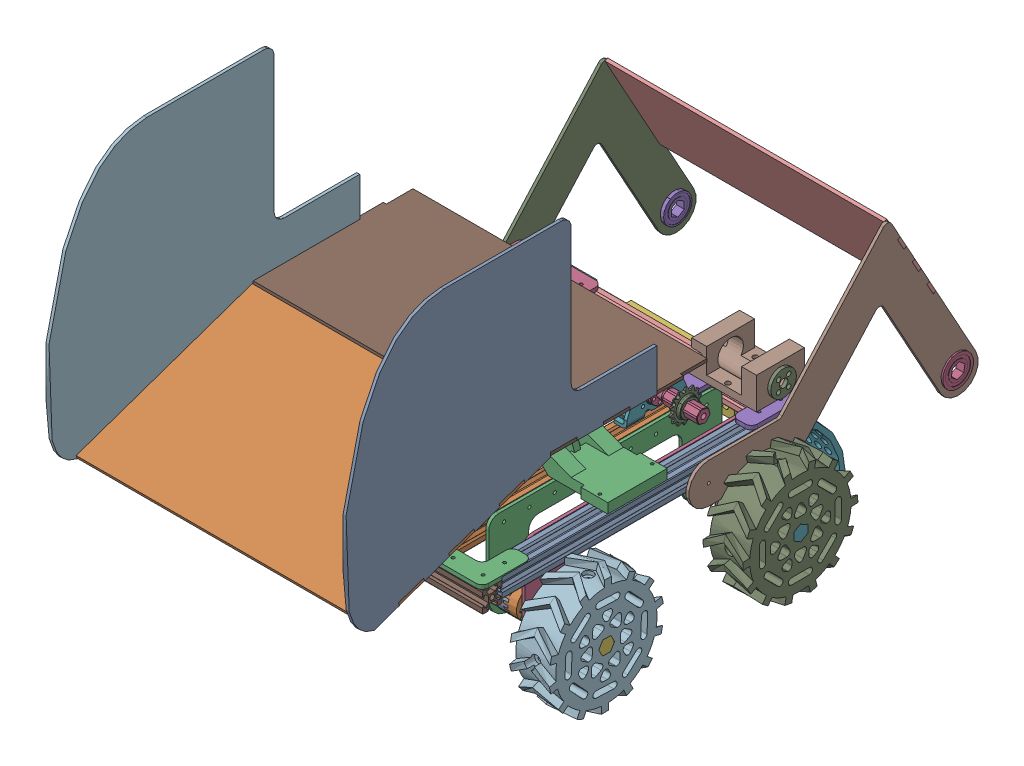
SolidWorks assembly Ensamblaje GOOOD BUENO V1, configuration Predeterminado. Lengths in mm.
Overall size (363.3 412.86 636.58).
70 component instances, 22 part files, 182 mates.
Components (placement in the parent):
- Perfil paredes-1: Perfil paredes [Predeterminado] at (-2.853 0.3396 -139.6276) size (20 20 280)
- Perfil paredes-3: Perfil paredes [Predeterminado] at (-62.853 -0.5145 -139.6276) size (20 20 280)
- PartCut-1: PartCut [Default] at (-49.853 -0.5145 -20.1572) x (0 0 1) z (0 -1 0) size (234 3 90)
- PartCut-2: PartCut [Default] at (-12.853 0.3396 -19.6675) x (0 0 1) z (0 -1 0) size (234 3 90)
- balero1-1: balero1 [Default] at (9.9745 -61.0728 77.1097) x (0 0.038595 0.999255) z (0 -0.999255 0.038595) size (30 21.24 30)
- eje hex_1-3: eje hex_1 [Default] at (-56.203 -60.313 75.8061) x (0 0.884678 0.466203) z (0 0.466203 -0.884678) size (16 105 13.86)
- eje hex_1-4: eje hex_1 [Default] at (-56.203 -61.5657 -116.9555) x (0 -0.5 -0.866025) z (0 -0.866025 0.5) size (16 105 13.86)
- balero1-2: balero1 [Default] at (-11.2655 -60.3108 -117.6536) x (0 -0.5 -0.866025) z (0 -0.866025 0.5) size (30 21.24 30)
- Llanta traccion-1: Llanta traccion [Default] at (28.797 -59.8526 -117.1472) x (0 0 -1) z (-1 0 0) size (115.27 115.22 40)
- sprocket-1: sprocket [Predeterminado] at (-23.9655 -60.2279 -117.7972) x (0 -0.994763 0.102207) z (-1 0 0) size (31.63 31.06 9.53)
- sprocket-2: sprocket [Predeterminado] at (-14.4405 -60.2279 -117.7972) x (0 -0.802979 0.596008) z (-1 0 0) size (31.63 31.06 9.53)
- Llanta traccion-2: Llanta traccion [Default] at (28.797 -60.479 77.5038) x (0 -0.999255 0.038595) z (-1 0 0) size (115.27 115.22 40)
- balero2-2: balero2 [Default] at (-48.2655 -61.1398 77.2368) x (0 -0.846083 0.533052) z (0 0.533052 0.846083) size (30 13 30)
- balero2-3: balero2 [Default] at (-39.7673 -61.1398 77.2368) x (0 -0.985001 0.172549) z (0 0.172549 0.985001) size (30 13 30)
- sprocket-3: sprocket [Predeterminado] at (-22.0048 -61.1398 77.2368) x (0 -0.703764 0.710434) z (-1 0 0) size (31.63 31.06 9.53)
- 1-2in Hex Adapter (REV-41-1620)-1: 1-2in Hex Adapter (REV-41-1620) [Default] at (-56.103 29.9855 -79.8) x (0 -0.955199 -0.295963) z (0 -0.295963 0.955199) size (22 46.85 22)
- 1-2in Hex Adapter (REV-41-1620)-2: 1-2in Hex Adapter (REV-41-1620) [Default] at (-206.603 30.8396 79.8) x (0 -0.552095 0.833781) z (0 -0.833781 -0.552095) size (22 46.85 22)
- UltraPlanetary Bent-1: UltraPlanetary Bent [Default] at (-204.853 30.8396 79.8) x (0 0 -1) z (1 0 0) size (60.41 41.01 15)
- UltraPlanetary Bent-2: UltraPlanetary Bent [Default] at (-60.853 29.9855 -79.8) x (0 0 1) z (-1 0 0) size (60.41 41.01 15)
- sprocket-21: sprocket [Predeterminado] at (-243.0667 30.8104 79.7982) x (0 0.061237 -0.998123) z (-1 0 0) size (31.63 31.06 9.53)
- sprocket-22: sprocket [Predeterminado] at (-29.5408 30.007 -79.8199) x (0 -0.679246 -0.733911) z (-1 0 0) size (31.63 31.06 9.53)
- Perfil paredes2-3: Perfil paredes2 [Predeterminado] at (-272.853 0.3396 -149.6276) x (0 0 -1) z (1 0 0) size (20 20 280)
- Perfil paredes2-4: Perfil paredes2 [Predeterminado] at (7.147 -3.1467 150.3724) x (0 0 1) z (-1 0 0) size (20 20 280)
- Perfil paredes-16: Perfil paredes [Predeterminado] at (-262.853 0.3396 -139.6276) size (20 20 280)
- Perfil paredes-17: Perfil paredes [Predeterminado] at (-202.853 0.3396 -139.6276) size (20 20 280)
- pieza soporte H-30: pieza soporte H [Predeterminado] at (-273.041 10.8533 133.768) x (1 0 0) z (0 -1 0) size (80 50 4)
- pieza soporte H-31: pieza soporte H [Predeterminado] at (-73.041 10.8533 133.768) x (1 0 0) z (0 -1 0) size (80 50 4)
- pieza soporte H-33: pieza soporte H [Predeterminado] at (-273.041 10.3396 -133.0232) x (1 0 0) z (0 1 0) size (80 50 4)
- pieza soporte H-34: pieza soporte H [Predeterminado] at (-73.041 10.3396 -133.0232) x (1 0 0) z (0 1 0) size (80 50 4)
- Motor REV-2: Motor REV [Predeterminado] at (-150.4708 15.4335 -105.4154) x (0 0.973917 -0.226904) z (0 0.226904 0.973917) size (39.5 129.75 43.54)
- Motor REV-3: Motor REV [Predeterminado] at (-112.2352 28.9925 50.3977) x (0 -0.939212 0.343339) z (0 0.343339 0.939212) size (39.5 129.75 43.54)
- Bumper (1)-3: Bumper (1) [Predeterminado] at (-167.853 -42.8554 -184.0714) size (70 88.26 45)
- Bumper (1)-4: Bumper (1) [Predeterminado] at (-272.853 -42.8554 -184.8214) size (70 88.26 45)
- IntakePropuesta-1: IntakePropuesta [Default] at (7.147 -21.3212 -199.703) x (0 0 -1) z (1 0 0) size (290.34 185.38 3)
- IntakePropuesta-2: IntakePropuesta [Default] at (-275.853 -21.3212 -199.703) x (0 0 -1) z (1 0 0) size (290.34 185.38 3)
- TapaRob-1: TapaRob [Default] at (-132.868 76.0202 -273.85) x (1 0 0) z (0 -0.48294 0.875654) size (286.03 114 3)
- FINAL-2: FINAL [Default] at (-137.1255 79.252 63.0539) x (0 0 1) z (-1 0 0) size (367.05 282.22 301.07)
  - placa-3: placa [Default] at (-104.5076 17.8118 2.7979) x (0 0 -1) z (0 -1 0) size (301.07 160.28 3)
  - LADOCAJA-16: LADOCAJA [Default] at (139.2351 16.3901 150.3351) x (0 0 1) z (-1 0 0) size (3 261.79 313.65)
  - LADOCAJA-17: LADOCAJA [Default] at (139.2351 16.3901 -147.7393) x (0 0 1) z (-1 0 0) size (3 261.79 313.65)
  - placanaja-1: placanaja [Predeterminado] at (153.6015 -28.7527 14.1489) x (0 0 -1) z (0.945056 -0.326908 0) size (301.07 3 186.9)
  - soporteizq-1: soporteizq [Predeterminado] at (-59.1696 -68.9123 -269.6703) x (0 0 -1) z (1 0 0) size (133.23 83.72 79.38)
- WCP-0783 (1)-29: WCP-0783 (1) [Default] at (3.797 -35.3661 -312.4416) x (0 -0.363378 0.931642) z (0 0.931642 0.363378) size (31.12 7.94 31.12)
- WCP-0783 (1)-30: WCP-0783 (1) [Default] at (-269.503 -35.3661 -312.4416) x (0 0.520565 -0.853822) z (0 0.853822 0.520565) size (31.12 7.94 31.12)
- WCP-0783 (1)-31: WCP-0783 (1) [Default] at (-46.503 -60.5145 -117.1572) x (0 -0.999907 0.013654) z (0 -0.013654 -0.999907) size (31.12 7.94 31.12)
- WCP-0783 (1)-32: WCP-0783 (1) [Default] at (-19.203 -59.6604 -116.6675) x (0 -0.480547 -0.876969) z (0 -0.876969 0.480547) size (31.12 7.94 31.12)
- WCP-0783 (1)-33: WCP-0783 (1) [Default] at (-246.503 -59.6604 -116.6675) x (0 -0.163854 -0.986485) z (0 0.986485 -0.163854) size (31.12 7.94 31.12)
- WCP-0783 (1)-34: WCP-0783 (1) [Default] at (-219.203 -60.5145 -117.1572) x (0 0.833867 0.551965) z (0 0.551965 -0.833867) size (31.12 7.94 31.12)
- WCP-0783 (1)-35: WCP-0783 (1) [Default] at (-219.203 -60.5145 76.8428) x (0 0.833867 0.551965) z (0 0.551965 -0.833867) size (31.12 7.94 31.12)
- WCP-0783 (1)-37: WCP-0783 (1) [Default] at (-246.503 -59.6604 77.3325) x (0 0.191015 -0.981587) z (0 0.981587 0.191015) size (31.12 7.94 31.12)
- WCP-0783 (1)-38: WCP-0783 (1) [Default] at (-19.203 -59.6604 77.3325) x (0 -0.3642 -0.931321) z (0 -0.931321 0.3642) size (31.12 7.94 31.12)
- WCP-0783 (1)-39: WCP-0783 (1) [Default] at (-46.503 -60.5145 76.8428) x (0 -0.463002 -0.886357) z (0 0.886357 -0.463002) size (31.12 7.94 31.12)
- balero2-24: balero2 [Default] at (-49.8156 -59.6604 -116.6675) x (0 -0.890112 -0.455741) z (0 -0.455741 0.890112) size (30 13 30)
- sprocket-26: sprocket [Predeterminado] at (-33.4905 -59.6604 -116.6675) x (0 -0.996368 0.085151) z (-1 0 0) size (31.63 31.06 9.53)
- balero2-26: balero2 [Default] at (-236.978 -59.6604 -116.6675) x (0 0.645951 -0.763379) z (0 -0.763379 -0.645951) size (30 13 30)
- balero2-29: balero2 [Default] at (-232.203 -60.5145 -117.1572) x (0 -0.573036 -0.819531) z (0 -0.819531 0.573036) size (30 13 30)
- sprocket-27: sprocket [Predeterminado] at (-234.1761 -59.6604 77.3325) x (0 -0.620534 0.78418) z (1 0 0) size (31.63 31.06 9.53)
- soportebump-3: soportebump [Default] at (-37.7876 -69.4237 -220.7073) x (1 0 0) z (0 0.006058 0.999982) size (73.25 131.02 90.26)
- soportder-1: soportder [Predeterminado] at (-399.0008 10.3396 -16.2917) x (-1 0 0) z (0 0 -1) size (138.04 83.72 94.74)
- Llanta traccion-14: Llanta traccion [Default] at (-294.503 -60.479 77.5038) x (0 -0.999255 0.038595) z (-1 0 0) size (115.27 115.22 40)
- eje hex_1-16: eje hex_1 [Default] at (-209.503 -61.7856 78.6005) x (0 0.884678 0.466203) z (0 -0.466203 0.884678) size (16 105 13.86)
- balero1-13: balero1 [Default] at (-275.6805 -61.0728 77.1097) x (0 0.038595 0.999255) z (0 0.999255 -0.038595) size (30 21.24 30)
- PartCut-13: PartCut [Default] at (-252.853 0.3396 -19.6675) x (0 0 -1) z (0 -1 0) size (234 3 90)
- sprocket-23: sprocket [Predeterminado] at (-243.7011 -61.1398 77.2368) x (0 -0.703764 0.710434) z (1 0 0) size (31.63 31.06 9.53)
- PartCut-14: PartCut [Default] at (-215.853 -0.5145 -20.1572) x (0 0 -1) z (0 -1 0) size (234 3 90)
- balero2-22: balero2 [Default] at (-217.4405 -61.1398 77.2368) x (0 -0.846083 0.533052) z (0 -0.533052 -0.846083) size (30 13 30)
- Llanta traccion-15: Llanta traccion [Default] at (-294.503 -59.8526 -117.1472) x (0 0 -1) z (-1 0 0) size (115.27 115.22 40)
- eje hex_1-17: eje hex_1 [Default] at (-209.503 -58.8302 -118.5349) x (0 -0.5 -0.866025) z (0 0.866025 -0.5) size (16 105 13.86)
- sprocket-24: sprocket [Predeterminado] at (-241.7405 -60.2279 -117.7972) x (0 -0.994763 0.102207) z (1 0 0) size (31.63 31.06 9.53)
- balero1-14: balero1 [Default] at (-254.4405 -60.3108 -117.6536) x (0 -0.5 -0.866025) z (0 0.866025 -0.5) size (30 21.24 30)
Mates (geometry in assembly coordinates):
- Coincidente1: coincident anti-aligned: plane of Perfil paredes-1 through (-60.2889 47.3396 140.3724) normal (0 0 1); plane of Perfil paredes-2 through (53.147 -4.2604 140) normal (0 0 -1)
- Coincidente2: coincident aligned: plane of Perfil paredes-1 through (1.747 -9.6604 186.3724) normal (0 -1 0); plane of Perfil paredes-2 through (53.147 -9.6604 145.4) normal (0 -1 0)
- Coincidente3: coincident aligned: plane of Perfil paredes-1 through (7.147 -4.2604 186.3724) normal (1 0 0); plane of Perfil paredes-2 through (7.147 47.3396 207.4359) normal (1 0 0)
- Coincidente4: coincident anti-aligned: plane of Perfil paredes-2 through (53.147 -4.2604 140) normal (0 0 -1); plane of Perfil paredes-3 through (-120.2889 46.4855 140.3724) normal (0 0 1)
- Coincidente5: coincident aligned: plane of Perfil paredes-2 through (53.147 -9.6604 145.4) normal (0 -1 0); plane of Perfil paredes-3 through (-67.453 -10.5145 186.3724) normal (0 -1 0)
- Coincidente6: coincident anti-aligned: plane of Perfil paredes-1 through (-12.103 9.5896 -139.6276) normal (0 0 -1); plane of Perfil paredes-4 through (53.147 -4.2604 -140) normal (0 0 1)
- Coincidente7: coincident aligned: plane of Perfil paredes-1 through (1.747 -9.6604 186.3724) normal (0 -1 0); plane of Perfil paredes-4 through (53.147 -9.6604 -145.4) normal (0 -1 0)
- Coincidente8: coincident aligned: plane of Perfil paredes-1 through (7.147 -4.2604 186.3724) normal (1 0 0); plane of Perfil paredes-4 through (7.147 -57.0963 -103) normal (1 0 0)
- Coincidente9: coincident anti-aligned: plane of Perfil paredes-2 through (53.147 -4.2604 140) normal (0 0 -1); plane of Perfil paredes-5 through (-278.1418 47.3396 140) normal (0 0 1)
- Coincidente10: coincident aligned: plane of Perfil paredes-2 through (53.147 -9.6604 145.4) normal (0 -1 0); plane of Perfil paredes-5 through (-225.306 -9.6604 170) normal (0 -1 0)
- Coincidente11: coincident anti-aligned: plane of Perfil paredes-2 through (53.147 -4.2604 140) normal (0 0 -1); plane of Perfil paredes-6 through (-320.2889 47.3396 140) normal (0 0 1)
- Coincidente12: coincident aligned: plane of Perfil paredes-2 through (53.147 -9.6604 145.4) normal (0 -1 0); plane of Perfil paredes-6 through (-267.453 -9.6604 170) normal (0 -1 0)
- Coincidente13: coincident aligned: plane of Perfil paredes-2 through (-272.853 9.5896 159.25) normal (-1 0 0); plane of Perfil paredes-6 through (-272.853 -4.2604 170) normal (-1 0 0)
- Coincidente14: coincident anti-aligned: plane of Perfil paredes-2 through (53.147 10.3396 154.6) normal (0 1 0); plane of pieza soporte H-1 through (-66.503 10.3396 116.35) normal (0 -1 0)
- Coincidente16: coincident aligned: plane of Perfil paredes-2 through (53.147 4.9396 160) normal (0 0 1); plane of pieza soporte H-1 through (-66.503 10.3396 160) normal (0 0 1)
- Coincidente18: coincident anti-aligned: plane of Perfil paredes-4 through (53.147 10.3396 -154.6) normal (0 1 0); plane of pieza soporte H-2 through (-66.503 10.3396 -116.35) normal (0 -1 0)
- Coincidente19: coincident aligned: plane of Perfil paredes-4 through (53.147 4.9396 -160) normal (0 0 -1); plane of pieza soporte H-2 through (-66.503 14.3396 -160) normal (0 0 -1)
- Coincidente21: coincident anti-aligned: plane of Perfil paredes-4 through (53.147 -9.6604 -154.6) normal (0 -1 0); plane of pieza soporte H-3 through (-66.503 -9.6604 -116.35) normal (0 1 0)
- Coincidente23: coincident aligned: plane of Perfil paredes-4 through (53.147 -4.2604 -160) normal (0 0 -1); plane of pieza soporte H-3 through (-66.503 -9.6604 -160) normal (0 0 -1)
- Coincidente25: coincident anti-aligned: plane of Perfil paredes-2 through (53.147 -9.6604 154.6) normal (0 -1 0); plane of pieza soporte H-4 through (-66.503 -9.6604 116.35) normal (0 1 0)
- Coincidente26: coincident aligned: plane of Perfil paredes-2 through (53.147 -4.2604 160) normal (0 0 1); plane of pieza soporte H-4 through (-66.503 -13.6604 160) normal (0 0 1)
- Coincidente28: coincident anti-aligned: plane of Perfil paredes-3 through (-52.853 4.0855 186.3724) normal (1 0 0); plane of PartCut-1 through (-52.853 -0.5145 -20.1572) normal (-1 0 0)
- Coincidente29: coincident aligned: plane of Perfil paredes-3 through (-58.253 9.4855 186.3724) normal (0 1 0); plane of PartCut-1 through (-52.853 9.4855 -20.1572) normal (0 1 0)
- Coincidente30: coincident anti-aligned: plane of Perfil paredes-1 through (-12.853 4.9396 186.3724) normal (-1 0 0); plane of PartCut-2 through (-12.853 0.3396 -19.6675) normal (1 0 0)
- Coincidente31: coincident aligned: plane of Perfil paredes-1 through (-7.453 10.3396 186.3724) normal (0 1 0); plane of PartCut-2 through (-15.853 10.3396 -19.6675) normal (0 1 0)
- Paralelo1: parallel anti-aligned: plane of PartCut-1 through (-49.853 -0.5145 -20.1572) normal (1 0 0); plane of PartCut-2 through (-15.853 0.3396 -19.6675) normal (-1 0 0)
- Coincidente33: coincident anti-aligned: plane of PartCut-1 through (-49.853 -0.5145 -20.1572) normal (1 0 0); plane of WCP-0783-1 through (-49.853 -74.2779 69.5899) normal (-1 0 0)
- Concéntrica1: concentric aligned: cylinder of PartCut-1 through (-52.853 -60.5145 76.8428) axis (1 0 0) radius 14.26; cylinder of WCP-0783-1 through (-56.203 -60.5145 76.8428) axis (1 0 0) radius 14.2748
- Coincidente34: coincident anti-aligned: plane of PartCut-2 through (-15.853 0.3396 -19.6675) normal (-1 0 0); plane of WCP-0783-2 through (-15.853 -46.4974 67.3402) normal (1 0 0)
- Concéntrica2: concentric anti-aligned: cylinder of PartCut-2 through (-15.853 -59.6604 77.3325) axis (1 0 0) radius 14.26; cylinder of WCP-0783-2 through (-9.503 -59.6604 75.6331) axis (-1 0 0) radius 14.2748
- Coincidente35: coincident anti-aligned: plane of PartCut-1 through (-49.853 -0.5145 -20.1572) normal (1 0 0); plane of WCP-0783-3 through (-49.853 -68.2933 -130.6303) normal (-1 0 0)
- Concéntrica3: concentric aligned: cylinder of PartCut-1 through (-52.853 -60.5145 -117.1572) axis (1 0 0) radius 14.26; cylinder of WCP-0783-3 through (-56.203 -60.5145 -117.1572) axis (1 0 0) radius 14.2748
- Coincidente37: coincident anti-aligned: plane of PartCut-2 through (-15.853 0.3396 -19.6675) normal (-1 0 0); plane of WCP-0783-4 through (-15.853 -51.8816 -131.84) normal (1 0 0)
- Concéntrica4: concentric anti-aligned: cylinder of PartCut-2 through (-15.853 -59.6604 -116.6675) axis (1 0 0) radius 14.26; cylinder of WCP-0783-4 through (-9.503 -59.6604 -118.3669) axis (-1 0 0) radius 14.2748
- Coincidente38: coincident aligned: plane of WCP-0783-1 through (-56.203 -69.0534 72.3431) normal (-1 0 0); plane of eje hex_1-1 through (-56.203 -58.2826 102.5031) normal (-1 0 0)
- Coincidente39: coincident anti-aligned: plane of WCP-0783-1 through (-56.203 -60.2311 84.1813) normal (0 0.466203 -0.884678); plane of eje hex_1-1 through (-56.203 -66.0204 97.1468) normal (0 -1 0)
- Paralelo2: parallel anti-aligned: plane of WCP-0783-1 through (-56.203 -60.798 69.5044) normal (0 -0.466203 0.884678); plane of eje hex_1-1 through (-56.203 -52.164 105.1468) normal (0 1 0)
- Coincidente41: coincident anti-aligned: plane of WCP-0783-1 through (-56.203 -66.7281 80.7575) normal (0 0.999255 -0.038595); plane of eje hex_1-1 through (-56.203 -59.0922 93.1468) normal (0 -0.5 -0.866025)
- Coincidente42: coincident anti-aligned: plane of WCP-0783-2 through (-9.503 -65.8739 79.5478) normal (0 0.466203 -0.884678); plane of eje hex_1-1 through (-56.203 -66.0204 97.1468) normal (0 -1 0)
- Paralelo3: parallel anti-aligned: plane of WCP-0783-1 through (-56.203 -54.0175 80.2666) normal (0 -0.533052 -0.846083); plane of eje hex_1-1 through (-56.203 -66.0204 105.1468) normal (0 -0.5 0.866025)
- Paralelo5: parallel anti-aligned: plane of WCP-0783-1 through (-56.203 -54.301 72.9282) normal (0 -0.999255 0.038595); plane of eje hex_1-1 through (-56.203 -59.0922 109.1468) normal (0 0.5 0.866025)
- Coincidente46: coincident aligned: plane of WCP-0783-3 through (-56.203 -65.3405 -125.516) normal (-1 0 0); plane of eje hex_1-2 through (-56.203 -57.976 -60.0582) normal (-1 0 0)
- Coincidente47: coincident anti-aligned: plane of WCP-0783-3 through (-56.203 -64.1865 -110.7972) normal (0 0.866025 -0.5); plane of eje hex_1-2 through (48.797 -63.3323 -53.9395) normal (0 -0.866025 0.5)
- Coincidente48: coincident anti-aligned: plane of WCP-0783-3 through (-56.203 -56.8426 -110.7972) normal (0 0 -1); plane of eje hex_1-2 through (48.797 -55.3323 -53.9395) normal (0 0 1)
- Coincidente49: coincident anti-aligned: plane of WCP-0783-4 through (-9.503 -55.9884 -124.7269) normal (0 0 1); plane of eje hex_1-2 through (48.797 -63.3323 -67.7959) normal (0 0 -1)
- Coincidente52: coincident anti-aligned: plane of WCP-0783-4 through (-9.503 -63.3323 -124.7269) normal (0 0.866025 0.5); plane of eje hex_1-2 through (48.797 -67.3323 -93.7494) normal (0 -0.866025 -0.5)
- Coincidente53: coincident aligned: plane of WCP-0783-1 through (-56.203 -69.0534 72.3431) normal (-1 0 0); plane of eje hex_1-3 through (-56.203 -60.313 75.8061) normal (-1 0 0)
- Coincidente54: coincident anti-aligned: plane of WCP-0783-1 through (-56.203 -60.798 69.5044) normal (0 -0.466203 0.884678); plane of eje hex_1-3 through (48.797 -61.3784 69.1985) normal (0 0.466203 -0.884678)
- Coincidente55: coincident anti-aligned: plane of WCP-0783-1 through (-56.203 -54.301 72.9282) normal (0 -0.999255 0.038595); plane of eje hex_1-3 through (48.797 -54.301 72.9282) normal (0 0.999255 -0.038595)
- Coincidente56: coincident anti-aligned: plane of WCP-0783-2 through (-9.503 -59.9438 68.2947) normal (0 0.533052 0.846083); plane of eje hex_1-3 through (48.797 -68.1471 73.463) normal (0 -0.533052 -0.846083)
- Coincidente57: coincident aligned: plane of WCP-0783-3 through (-56.203 -65.3405 -125.516) normal (-1 0 0); plane of eje hex_1-4 through (-56.203 -61.5657 -116.9555) normal (-1 0 0)
- Coincidente58: coincident anti-aligned: plane of WCP-0783-3 through (-56.203 -56.8426 -110.7972) normal (0 0 -1); plane of eje hex_1-4 through (48.797 -56.1865 -110.7972) normal (0 0 1)
- Coincidente59: coincident anti-aligned: plane of WCP-0783-3 through (-56.203 -64.1865 -110.7972) normal (0 0.866025 -0.5); plane of eje hex_1-4 through (48.797 -64.1865 -110.7972) normal (0 -0.866025 0.5)
- Coincidente60: coincident anti-aligned: plane of WCP-0783-2 through (-9.503 -51.494 70.4881) normal (1 0 0); plane of balero1-1 through (-11.2655 -61.0728 77.1097) normal (-1 0 0)
- Coincidente61: coincident anti-aligned: plane of balero1-1 through (-37.2655 -67.9116 81.4184) normal (0 0.466203 -0.884678); plane of eje hex_1-3 through (48.797 -60.7609 85.1866) normal (0 -0.466203 0.884678)
- Coincidente62: coincident anti-aligned: plane of balero1-1 through (-37.2655 -60.7609 85.1866) normal (0 -0.533052 -0.846083); plane of eje hex_1-3 through (48.797 -53.9922 80.9222) normal (0 0.533052 0.846083)
- Coincidente63: coincident anti-aligned: plane of WCP-0783-4 through (-9.503 -54.8344 -126.7257) normal (1 0 0); plane of balero1-2 through (-11.2655 -60.3108 -117.6536) normal (-1 0 0)
- Coincidente64: coincident anti-aligned: plane of WCP-0783-4 through (-9.503 -54.8344 -126.7257) normal (1 0 0); plane of balero1-2 through (-11.2655 -60.3108 -117.6536) normal (-1 0 0)
- Coincidente65: coincident anti-aligned: plane of eje hex_1-4 through (48.797 -52.1865 -117.7254) normal (0 0.866025 0.5); plane of balero1-2 through (35.9745 -52.2279 -117.6536) normal (0 -0.866025 -0.5)
- Coincidente66: coincident anti-aligned: plane of eje hex_1-4 through (48.797 -64.1865 -124.6536) normal (0 0 -1); plane of balero1-2 through (35.9745 -64.3523 -124.6536) normal (0 0 1)
- Coincidente67: coincident aligned: plane of eje hex_1-4 through (48.797 -61.5657 -116.9555) normal (1 0 0); plane of Llanta traccion-1 through (48.797 -59.8526 -117.1472) normal (1 0 0)
- Coincidente68: coincident anti-aligned: plane of eje hex_1-4 through (48.797 -52.1865 -117.7254) normal (0 0.866025 0.5); plane of Llanta traccion-1 through (8.797 -54.3534 -113.9722) normal (0 -0.866025 -0.5)
- Coincidente69: coincident anti-aligned: plane of eje hex_1-4 through (48.797 -56.1865 -110.7972) normal (0 0 1); plane of Llanta traccion-1 through (8.797 -59.8526 -110.7972) normal (0 0 -1)
- Coincidente72: coincident anti-aligned: plane of eje hex_1-4 through (48.797 -52.1865 -117.7254) normal (0 0.866025 0.5); plane of balero2-1 through (-72.503 -56.1865 -110.7972) normal (0 -0.866025 -0.5)
- Coincidente73: coincident anti-aligned: plane of eje hex_1-4 through (48.797 -56.1865 -110.7972) normal (0 0 1); plane of balero2-1 through (-72.503 -64.2694 -110.7972) normal (0 0 -1)
- Concéntrica5: concentric anti-aligned: cylinder of balero2-1 through (-46.503 -60.2279 -117.7972) axis (1 0 0) radius 15; cone of sprocket-1 through (-28.728 -60.2279 -117.7972) axis (-1 0 0)
- Coincidente75: coincident anti-aligned: plane of sprocket-1 through (-19.203 -60.2279 -117.7972) normal (1 0 0); plane of sprocket-2 through (-19.203 -60.2279 -117.7972) normal (-1 0 0)
- Concéntrica6: concentric anti-aligned: cylinder of balero2-1 through (-46.503 -60.2279 -117.7972) axis (1 0 0) radius 15; cone of sprocket-2 through (-19.203 -60.2279 -117.7972) axis (-1 0 0)
- Coincidente76: coincident aligned: plane of eje hex_1-3 through (48.797 -60.313 75.8061) normal (1 0 0); plane of Llanta traccion-2 through (48.797 -60.479 77.5038) normal (1 0 0)
- Coincidente77: coincident anti-aligned: plane of eje hex_1-3 through (48.797 -54.301 72.9282) normal (0 0.999255 -0.038595); plane of Llanta traccion-2 through (8.797 -54.1337 77.2588) normal (0 -0.999255 0.038595)
- Coincidente78: coincident anti-aligned: plane of eje hex_1-3 through (48.797 -53.9922 80.9222) normal (0 0.533052 0.846083); plane of Llanta traccion-2 through (8.797 -57.0941 82.8765) normal (0 -0.533052 -0.846083)
- Coincidente79: coincident anti-aligned: plane of WCP-0783-1 through (-48.2655 -66.1322 73.8825) normal (1 0 0); plane of balero2-2 through (-48.2655 -61.1398 77.2368) normal (-1 0 0)
- Coincidente80: coincident anti-aligned: plane of eje hex_1-3 through (48.797 -61.3784 69.1985) normal (0 0.466203 -0.884678); plane of balero2-2 through (-9.2655 -61.4517 69.1599) normal (0 -0.466203 0.884678)
- Coincidente81: coincident anti-aligned: plane of eje hex_1-3 through (48.797 -54.301 72.9282) normal (0 0.999255 -0.038595); plane of balero2-2 through (-9.2655 -54.301 72.9282) normal (0 -0.999255 0.038595)
- Coincidente83: coincident anti-aligned: plane of WCP-0783-2 through (-17.4405 -54.2877 72.2483) normal (-1 0 0); plane of sprocket-3 through (-17.2423 -61.1398 77.2368) normal (1 0 0)
- Concéntrica8: concentric aligned: cylinder of balero2-2 through (-35.2655 -61.1398 77.2368) axis (-1 0 0) radius 15; cone of sprocket-3 through (-26.7673 -61.1398 77.2368) axis (-1 0 0)
- Coincidente84: coincident anti-aligned: plane of balero2-3 through (-26.7673 -61.1398 77.2368) normal (1 0 0); plane of sprocket-3 through (-26.7673 -61.1398 77.2368) normal (-1 0 0)
- Concéntrica9: concentric aligned: cylinder of balero2-2 through (-35.2655 -61.1398 77.2368) axis (-1 0 0) radius 15; cylinder of balero2-3 through (-26.7673 -61.1398 77.2368) axis (-1 0 0) radius 15
- Coincidente87: coincident anti-aligned: plane of Perfil paredes-1 through (7.147 4.9396 186.3724) normal (1 0 0); plane of IntakeZT2-1 through (7.147 -164.6227 -236.8898) normal (-1 0 0)
- Coincidente88: coincident aligned: plane of Perfil paredes-1 through (1.747 10.3396 186.3724) normal (0 1 0); plane of IntakeZT2-1 through (7.147 10.3396 -236.8898) normal (0 1 0)
- Coincidente95: coincident aligned: plane of 1-2in Hex Adapter (REV-41-1620)-2 through (-204.853 30.8396 79.8) normal (1 0 0); plane of UltraPlanetary Bent-1 through (-204.853 30.8396 79.8) normal (1 0 0)
- Concéntrica12: concentric aligned: cylinder of 1-2in Hex Adapter (REV-41-1620)-2 through (-209.603 30.8396 79.8) axis (1 0 0) radius 11; cylinder of UltraPlanetary Bent-1 through (-214.853 30.8396 79.8) axis (1 0 0) radius 12
- Coincidente96: coincident anti-aligned: plane of REV-41-1600-1/REV-41-1600.STEP-1/REV-41-1604_1.STEP-1/REV-40-1606_Through Hole_1.STEP-1 through (-206.603 30.8396 79.8) normal (-1 0 0); plane of 1-2in Hex Adapter (REV-41-1620)-2 through (-206.603 30.8396 79.8) normal (1 0 0)
- Concéntrica13: concentric anti-aligned: cylinder of REV-41-1600-1/REV-41-1600.STEP-1/REV-41-1604_1.STEP-1/REV-40-1606_Through Hole_1.STEP-1 through (-199.603 30.8396 79.8) axis (-1 0 0) radius 11; circle of UltraPlanetary Bent-1
- Coincidente97: coincident anti-aligned: plane of Perfil paredes-3 through (-58.253 9.4855 186.3724) normal (0 1 0); plane of UltraPlanetary Bent-2 through (-60.853 9.4855 -79.8) normal (0 -1 0)
- Coincidente98: coincident aligned: plane of Perfil paredes-3 through (-72.853 4.0855 186.3724) normal (-1 0 0); plane of UltraPlanetary Bent-2 through (-72.853 9.4855 -110) normal (-1 0 0)
- Coincidente100: coincident anti-aligned: plane of 1-2in Hex Adapter (REV-41-1620)-1 through (-57.853 29.9855 -79.8) normal (-1 0 0); plane of UltraPlanetary Bent-2 through (-57.853 29.9855 -79.8) normal (1 0 0)
- Concéntrica14: concentric aligned: cylinder of 1-2in Hex Adapter (REV-41-1620)-1 through (-53.103 29.9855 -79.8) axis (-1 0 0) radius 11; cylinder of UltraPlanetary Bent-2 through (-50.853 29.9855 -79.8) axis (-1 0 0) radius 12
- Coincidente101: coincident anti-aligned: plane of 1-2in Hex Adapter (REV-41-1620)-1 through (-57.853 29.9855 -79.8) normal (-1 0 0); plane of REV-41-1600-2/REV-41-1600.STEP-1/REV-41-1604_1.STEP-1/REV-40-1606_Through Hole_1.STEP-1 through (-57.853 29.9855 -79.8) normal (1 0 0)
- Concéntrica15: concentric anti-aligned: cylinder of UltraPlanetary Bent-2 through (-50.853 29.9855 -79.8) axis (-1 0 0) radius 12; cylinder of REV-41-1600-2/REV-41-1600.STEP-1/REV-41-1604_1.STEP-1/REV-40-1606_Through Hole_1.STEP-1 through (-64.853 29.9855 -79.8) axis (1 0 0) radius 11
- Coincidente102: coincident anti-aligned: plane of 1-2in Hex Adapter (REV-41-1620)-2 through (-251.703 36.1342 83.3058) normal (0 0.833781 0.552095); plane of Sprocket-20
- Coincidente103: coincident anti-aligned: plane of 1-2in Hex Adapter (REV-41-1620)-2 through (-251.703 36.1342 83.3058) normal (0 0.833781 0.552095); plane of sprocket-21 through (-238.3042 34.0939 86.387) normal (0 -0.833781 -0.552095)
- Coincidente107: coincident anti-aligned: plane of 1-2in Hex Adapter (REV-41-1620)-2 through (-251.703 36.523 76.9677) normal (0 0.895019 -0.446029); plane of sprocket-21 through (-238.3042 38.1582 80.249) normal (0 -0.895019 0.446029)
- Coincidente108: coincident anti-aligned: plane of 1-2in Hex Adapter (REV-41-1620)-1 through (-11.003 23.7929 -78.3948) normal (0 -0.975208 0.221289); plane of sprocket-22 through (-24.7783 22.9751 -81.9987) normal (0 0.975208 -0.221289)
- Coincidente109: coincident anti-aligned: plane of 1-2in Hex Adapter (REV-41-1620)-1 through (-11.003 28.1061 -73.7345) normal (0 -0.295963 0.955199); plane of sprocket-22 through (-24.7783 24.6042 -74.8195) normal (0 0.295963 -0.955199)
- Coincidente110: coincident: plane of Perfil paredes-1 through (-12.103 9.5896 -139.6276) normal (0 0 -1); plane of Perfil paredes2-3 through (7.147 4.9396 -139.6276) normal (0 0 1)
- Coincidente114: coincident anti-aligned: plane of Perfil paredes-1 through (-60.2889 47.3396 140.3724) normal (0 0 1); plane of Perfil paredes2-4 through (-272.853 1.4533 140.3724) normal (0 0 -1)
- Coincidente120: coincident anti-aligned: plane of Perfil paredes-3 through (-120.2889 46.4855 140.3724) normal (0 0 1); plane of Perfil paredes2-4 through (-272.853 1.4533 140.3724) normal (0 0 -1)
- Coincidente123: coincident aligned: plane of Perfil paredes-1 through (7.147 4.9396 186.3724) normal (1 0 0); plane of Perfil paredes2-4 through (7.147 6.1033 141.1224) normal (1 0 0)
- Coincidente124: coincident: plane of Perfil paredes2-3 through (7.147 4.9396 -139.6276) normal (0 0 1); plane of Perfil paredes-17 through (-212.103 9.5896 -139.6276) normal (0 0 -1)
- Coincidente125: coincident: plane of Perfil paredes2-3 through (7.147 10.3396 -145.0276) normal (0 1 0); plane of Perfil paredes-17 through (-198.253 10.3396 186.3724) normal (0 1 0)
- Coincidente126: coincident anti-aligned: plane of Perfil paredes2-3 through (7.147 4.9396 -139.6276) normal (0 0 1); plane of Perfil paredes-16 through (-272.103 9.5896 -139.6276) normal (0 0 -1)
- Coincidente127: coincident aligned: plane of Perfil paredes2-3 through (7.147 10.3396 -145.0276) normal (0 1 0); plane of Perfil paredes-16 through (-258.253 10.3396 186.3724) normal (0 1 0)
- Coincidente131: coincident: plane of UltraPlanetary Bent-1 through (-204.853 10.3396 79.8) normal (0 -1 0); plane of Perfil paredes-17 through (-207.453 10.3396 186.3724) normal (0 1 0)
- Coincidente132: coincident: plane of UltraPlanetary Bent-1 through (-192.853 10.3396 110) normal (1 0 0); plane of Perfil paredes-17 through (-192.853 4.9396 186.3724) normal (1 0 0)
- Coincidente133: coincident anti-aligned: plane of Perfil paredes2-4 through (-272.853 6.8533 154.9724) normal (0 1 0); plane of pieza soporte H-30 through (-266.503 6.8533 116.7224) normal (0 -1 0)
- Coincidente134: coincident aligned: plane of Perfil paredes-16 through (-272.853 4.9396 186.3724) normal (-1 0 0); plane of pieza soporte H-30 through (-272.853 6.8533 140.3724) normal (-1 0 0)
- Coincidente135: coincident aligned: plane of Perfil paredes2-4 through (-272.853 1.4533 160.3724) normal (0 0 1); plane of pieza soporte H-30 through (-266.503 6.8533 160.3724) normal (0 0 1)
- Coincidente136: coincident anti-aligned: plane of Perfil paredes2-4 through (-272.853 6.8533 154.9724) normal (0 1 0); plane of pieza soporte H-31 through (-66.503 6.8533 116.7224) normal (0 -1 0)
- Coincidente137: coincident anti-aligned: plane of Perfil paredes2-4 through (-272.853 6.8533 154.9724) normal (0 1 0); plane of pieza soporte H-31 through (-66.503 6.8533 116.7224) normal (0 -1 0)
- Coincidente138: coincident: line of Perfil paredes2-4 through (-272.853 1.4533 160.3724) axis (1 0 0); plane of pieza soporte H-31 through (-66.503 6.8533 160.3724) normal (0 0 1)
- Coincidente139: coincident: plane of Perfil paredes-1 through (7.147 4.9396 186.3724) normal (1 0 0); plane of pieza soporte H-31 through (7.147 6.8533 140.3724) normal (1 0 0)
- Coincidente141: coincident: plane of Perfil paredes2-3 through (7.147 10.3396 -154.2276) normal (0 1 0); plane of pieza soporte H-33 through (-266.503 10.3396 -115.9776) normal (0 -1 0)
- Coincidente142: coincident: plane of Perfil paredes2-3 through (-272.853 9.5896 -140.3776) normal (-1 0 0); plane of pieza soporte H-33 through (-272.853 14.3396 -139.6276) normal (-1 0 0)
- Coincidente143: coincident: plane of Perfil paredes2-3 through (7.147 4.9396 -159.6276) normal (0 0 -1); plane of pieza soporte H-33 through (-266.503 14.3396 -159.6276) normal (0 0 -1)
- Coincidente144: coincident: plane of Perfil paredes2-3 through (7.147 10.3396 -154.2276) normal (0 1 0); plane of pieza soporte H-34 through (-66.503 10.3396 -115.9776) normal (0 -1 0)
- Coincidente145: coincident: plane of Perfil paredes2-3 through (7.147 9.5896 -140.3776) normal (1 0 0); plane of pieza soporte H-34 through (7.147 14.3396 -139.6276) normal (1 0 0)
- Coincidente146: coincident: plane of Perfil paredes2-3 through (7.147 4.9396 -159.6276) normal (0 0 -1); plane of pieza soporte H-34 through (-66.503 14.3396 -159.6276) normal (0 0 -1)
- Coincidente147: coincident anti-aligned: plane of 1-2in Hex Adapter (REV-41-1620)-1 through (-56.103 29.9855 -79.8) normal (-1 0 0); plane of Motor REV-2 through (-56.103 29.9855 -79.8) normal (1 0 0)
- Concéntrica16: concentric anti-aligned: cylinder of UltraPlanetary Bent-2 through (-50.853 29.9855 -79.8) axis (-1 0 0) radius 12; cylinder of Motor REV-2 through (-63.103 29.9855 -79.8) axis (1 0 0) radius 11
- Coincidente152: coincident anti-aligned: plane of 1-2in Hex Adapter (REV-41-1620)-2 through (-206.603 30.8396 79.8) normal (1 0 0); plane of Motor REV-3 through (-206.603 30.8396 79.8) normal (-1 0 0)
- Concéntrica19: concentric anti-aligned: cylinder of UltraPlanetary Bent-1 through (-214.853 30.8396 79.8) axis (1 0 0) radius 12; cylinder of Motor REV-3 through (-199.603 30.8396 79.8) axis (-1 0 0) radius 11
- Coincidente153: coincident: plane of Perfil paredes2-3 through (7.147 4.9396 -159.6276) normal (0 0 -1); plane of Bumper (1)-1 through (7.147 10.3396 -159.6276) normal (0 0 1)
- Coincidente154: coincident: plane of Perfil paredes2-3 through (7.147 10.3396 -154.2276) normal (0 1 0); plane of Bumper (1)-1 through (7.147 10.3396 -159.6276) normal (0 1 0)
- Coincidente155: coincident: line of Perfil paredes2-3 through (7.147 10.3396 -158.8776) axis (0 0 1); line of Bumper (1)-1 through (7.147 10.3396 -164.6276) axis (0 0 1)
- Coincidente156: coincident: plane of Perfil paredes2-3 through (7.147 4.9396 -159.6276) normal (0 0 -1); plane of Bumper (1)-2 through (-113.5113 10.3396 -159.6276) normal (0 0 1)
- Coincidente157: coincident: plane of Perfil paredes2-3 through (7.147 10.3396 -154.2276) normal (0 1 0); plane of Bumper (1)-2 through (-113.5113 10.3396 -159.6276) normal (0 1 0)
- Coincidente160: coincident anti-aligned: plane of Perfil paredes2-3 through (7.147 4.9396 -159.6276) normal (0 0 -1); plane of soportebump-2/Bumper-1 through (7.147 9.0338 -159.6276) normal (0 0 1)
- Coincidente161: coincident anti-aligned: plane of IntakeZT2-1 through (7.147 -164.6227 -236.8898) normal (-1 0 0); plane of soportebump-2/soporte Motor banda-1 through (7.147 7.7764 -159.6276) normal (1 0 0)
- Coincidente172: coincident: point of assembly; point of assembly; moEndPointRef_w of Perfil paredes2-3; moEndPointRef_w of Bumper (1)-3
- Coincidente173: coincident anti-aligned: plane of Perfil paredes2-3 through (7.147 4.9396 -159.6276) normal (0 0 -1); plane of Bumper (1)-4 through (-202.853 10.3396 -159.6276) normal (0 0 1)
- Coincidente174: coincident aligned: plane of Perfil paredes2-3 through (7.147 10.3396 -154.2276) normal (0 1 0); plane of Bumper (1)-4 through (-202.853 10.3396 -159.6276) normal (0 1 0)
- Coincidente178: coincident anti-aligned: plane of Perfil paredes-1 through (7.147 4.9396 186.3724) normal (1 0 0); plane of IntakePropuesta-1 through (7.147 -9.6604 -63.8918) normal (-1 0 0)
- Coincidente179: coincident aligned: plane of Perfil paredes-1 through (1.747 10.3396 186.3724) normal (0 1 0); plane of IntakePropuesta-1 through (10.147 10.3396 -63.8918) normal (0 1 0)
- Coincidente182: coincident anti-aligned: plane of Perfil paredes-16 through (-272.853 4.9396 186.3724) normal (-1 0 0); plane of IntakePropuesta-2 through (-272.853 -9.6604 -63.8918) normal (1 0 0)
- Coincidente183: coincident aligned: plane of Perfil paredes-16 through (-267.453 10.3396 186.3724) normal (0 1 0); plane of IntakePropuesta-2 through (-272.853 10.3396 -63.8918) normal (0 1 0)
- Paralelo8: parallel aligned: line of IntakePropuesta-1 through (10.147 10.3396 -133.8297) axis (-1 0 0); line of IntakePropuesta-2 through (-272.853 10.3396 -133.8297) axis (-1 0 0)
- Coincidente199: coincident aligned: plane of IntakePropuesta-1 through (10.147 -9.6604 -63.8918) normal (1 0 0); plane of TapaRob-1 through (10.147 122.7324 -244.6614) normal (1 0 0)
- Coincidente200: coincident anti-aligned: plane of IntakePropuesta-1 through (7.147 31.2888 -295.0942) normal (0 0.48294 -0.875654); plane of TapaRob-1 through (-132.868 74.5714 -271.223) normal (0 -0.48294 0.875654)
- Coincidente201: coincident anti-aligned: plane of IntakePropuesta-1 through (10.147 80.2843 -268.0723) normal (0 -0.875654 -0.48294); plane of TapaRob-1 through (-132.868 81.7331 -270.6993) normal (0 0.875654 0.48294)
- Coincidente203: coincident anti-aligned: plane of IntakePropuesta-2 through (-272.853 106.9706 -253.3543) normal (0 -0.875654 -0.48294); plane of TapaRob-1 through (-132.868 108.4194 -255.9812) normal (0 0.875654 0.48294)
- Coincidente204: coincident anti-aligned: plane of Perfil paredes-1 through (1.747 10.3396 186.3724) normal (0 1 0); plane of FINAL-2/soportder-1 through (133.2948 10.3396 4.5525) normal (0 -1 0)
- Coincidente205: coincident aligned: plane of Perfil paredes-1 through (7.147 4.9396 186.3724) normal (1 0 0); plane of FINAL-2/soportder-1 through (7.147 20.3396 -25.2174) normal (1 0 0)
- Coincidente210: coincident aligned: line of Perfil paredes-1 through (6.397 10.3396 140.3724) axis (0 0 -1); line of FINAL-2/soporteizq-1 through (6.397 10.3396 33.6542) axis (0 0 -1)
- Paralelo19: parallel aligned: plane of Perfil paredes-1 through (7.147 4.9396 186.3724) normal (1 0 0); plane of FINAL-2/soporteizq-1 through (6.397 20.3396 -25.8855) normal (1 0 0)
- Concentric1: concentric aligned: circle of IntakePropuesta-1; circle of WCP-0783-29
- Concentric2: concentric anti-aligned: circle of IntakePropuesta-2; circle of WCP-0783-30
- Coincident2: coincident anti-aligned: plane of IntakePropuesta-2 through (-275.853 -9.6604 -63.8918) normal (-1 0 0); plane of WCP-0783-30 through (-275.853 -27.2675 -325.7249) normal (1 0 0)
- Concentric4: concentric aligned: circle of PartCut-1; circle of WCP-0783-31
- Coincident3: coincident anti-aligned: plane of PartCut-1 through (-52.853 -0.5145 -20.1572) normal (-1 0 0); plane of WCP-0783-31 through (-52.853 -76.0706 -116.9447) normal (1 0 0)
- Concentric5: concentric anti-aligned: circle of PartCut-2; circle of WCP-0783-32
- Coincident4: coincident anti-aligned: plane of PartCut-2 through (-12.853 0.3396 -19.6675) normal (1 0 0); plane of WCP-0783-32 through (-12.853 -67.1365 -130.3109) normal (-1 0 0)
- Concentric6: concentric aligned: circle of PartCut-13; circle of WCP-0783-33
- Coincident5: coincident anti-aligned: plane of PartCut-13 through (-252.853 0.3396 -19.6675) normal (-1 0 0); plane of WCP-0783-33 through (-252.853 -62.2095 -132.0147) normal (1 0 0)
- Coincident6: coincident anti-aligned: plane of balero1-14 through (-254.4405 -60.3108 -117.6536) normal (1 0 0); plane of WCP-0783-33 through (-254.4405 -61.7413 -129.1958) normal (-1 0 0)
- Concentric7: concentric anti-aligned: circle of PartCut-14; circle of WCP-0783-34
- Concentric8: concentric aligned: circle of PartCut-14; circle of WCP-0783-35
- Coincident8: coincident anti-aligned: plane of PartCut-14 through (-212.853 -0.5145 -20.1572) normal (1 0 0); plane of WCP-0783-35 through (-212.853 -47.5416 85.43) normal (-1 0 0)
- Concentric10: concentric anti-aligned: circle of PartCut-13; circle of WCP-0783-37
- Coincident9: coincident anti-aligned: plane of PartCut-13 through (-252.853 0.3396 -19.6675) normal (-1 0 0); plane of WCP-0783-37 through (-252.853 -56.6886 62.0615) normal (1 0 0)
- Coincident10: coincident anti-aligned: plane of balero1-13 through (-254.4405 -61.0728 77.1097) normal (1 0 0); plane of WCP-0783-37 through (-254.4405 -57.2345 64.8664) normal (-1 0 0)
- Concentric11: concentric aligned: circle of PartCut-2; circle of WCP-0783-38
- Coincident11: coincident anti-aligned: plane of PartCut-2 through (-12.853 0.3396 -19.6675) normal (1 0 0); plane of WCP-0783-38 through (-12.853 -65.3264 62.8435) normal (-1 0 0)
- Concentric13: concentric anti-aligned: circle of PartCut-1; circle of WCP-0783-39
- Coincident12: coincident anti-aligned: plane of PartCut-1 through (-52.853 -0.5145 -20.1572) normal (-1 0 0); plane of WCP-0783-39 through (-52.853 -67.7177 63.0533) normal (1 0 0)
- Coincident13: coincident anti-aligned: plane of sprocket-24 through (-246.503 -60.2279 -117.7972) normal (-1 0 0); plane of WCP-0783-33 through (-246.503 -61.9993 -130.7493) normal (1 0 0)
- Concentric14: concentric anti-aligned: circle of PartCut-2; circle of balero2-24
- Coincident25: coincident: plane of WCP-0783-31 through (-46.503 -74.788 -116.9622) normal (1 0 0); plane of balero2-25 through (-46.503 -59.6604 -118.3669) normal (-1 0 0)
- Concentric18: concentric aligned: circle of WCP-0783-32; circle of sprocket-26
- Coincident27: coincident anti-aligned: plane of sprocket-1 through (-28.728 -60.2279 -117.7972) normal (-1 0 0); plane of sprocket-26 through (-28.728 -59.6604 -116.6675) normal (1 0 0)
- Concentric19: concentric anti-aligned: circle of PartCut-13; circle of balero2-26
- Coincident28: coincident anti-aligned: plane of sprocket-24 through (-236.978 -60.2279 -117.7972) normal (1 0 0); plane of balero2-26 through (-236.978 -59.6604 -116.6675) normal (-1 0 0)
- Coincident35: coincident anti-aligned: plane of WCP-0783-34 through (-219.203 -48.6112 -109.278) normal (-1 0 0); plane of balero2-29 through (-219.203 -60.5145 -117.1572) normal (1 0 0)
- Concentric20: concentric anti-aligned: circle of PartCut-14; circle of balero2-29
- Concentric23: concentric anti-aligned: circle of WCP-0783-37; circle of sprocket-27
- Coincident40: coincident anti-aligned: plane of sprocket-23 through (-238.9386 -61.1398 77.2368) normal (1 0 0); plane of sprocket-27 through (-238.9386 -59.6604 77.3325) normal (-1 0 0)
- Coincident47: coincident anti-aligned: plane of IntakePropuesta-1 through (7.147 -9.6604 -63.8918) normal (-1 0 0); plane of soportebump-3 through (7.147 13.2178 -159.7745) normal (1 0 0)
- Coincident55: coincident: plane of Perfil paredes2-3 through (7.147 -4.2604 -159.6276) normal (0 0 -1); line of soportebump-3 through (7.147 -9.7822 -159.6276) axis (-1 0 0)
- Coincident56: coincident anti-aligned: plane of Perfil paredes-16 through (-267.453 10.3396 186.3724) normal (0 1 0); plane of soportder-1 through (-399.0008 10.3396 -16.2917) normal (0 -1 0)
- Coincident69: coincident aligned: plane of Perfil paredes-16 through (-272.853 4.9396 186.3724) normal (-1 0 0); plane of soportder-1 through (-272.853 20.3396 13.4782) normal (-1 0 0)
- Parallel14: parallel aligned: line of FINAL-2/soporteizq-1 through (6.397 20.3396 -25.8855) axis (-1 0 0); line of soportder-1 through (-245.8509 20.3396 -46.0615) axis (-1 0 0)
- Parallel15: parallel aligned: line of FINAL-2/soporteizq-1 through (6.397 20.3396 -25.8855) axis (-1 0 0); line of soportder-1 through (-245.8509 20.3396 -46.0615) axis (-1 0 0)
